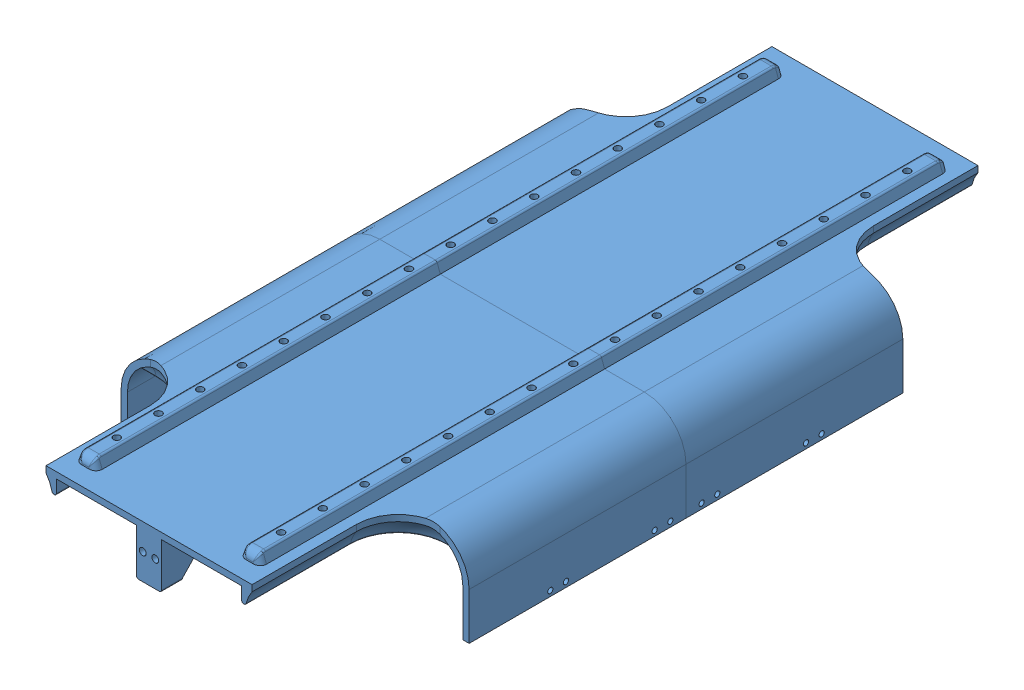
SolidWorks assembly Full Cover, configuration Default. Lengths in mm.
Overall size (166.72 47.1 347.8).
2 component instances, 1 part files, 3 mates.
Components (placement in the parent):
- Cover-1: Cover [Default] at (-4.3359 146.0318 132.4671) size (166.72 47.1 173.9)
- Cover-2: Cover [Default] at (-64.1437 146.0318 132.4671) x (-1 0 0) z (0 0 -1) size (166.72 47.1 173.9)
Mates (geometry in assembly coordinates):
- Coincident1: coincident: plane of Cover-1 through (-4.3359 146.0318 132.4671) normal (0 0 -1); plane of Cover-2 through (-64.1437 146.0318 132.4671) normal (0 0 1)
- Coincident2: coincident: plane of Cover-1 through (49.1202 146.0318 306.3671) normal (1 0 0); plane of Cover-2 through (49.1202 146.0318 -41.4329) normal (1 0 0)
- Coincident3: coincident aligned: plane of Cover-1 through (-4.3359 131.6799 306.3671) normal (0 -1 0); plane of Cover-2 through (-4.3359 131.6799 -41.4329) normal (0 -1 0)
